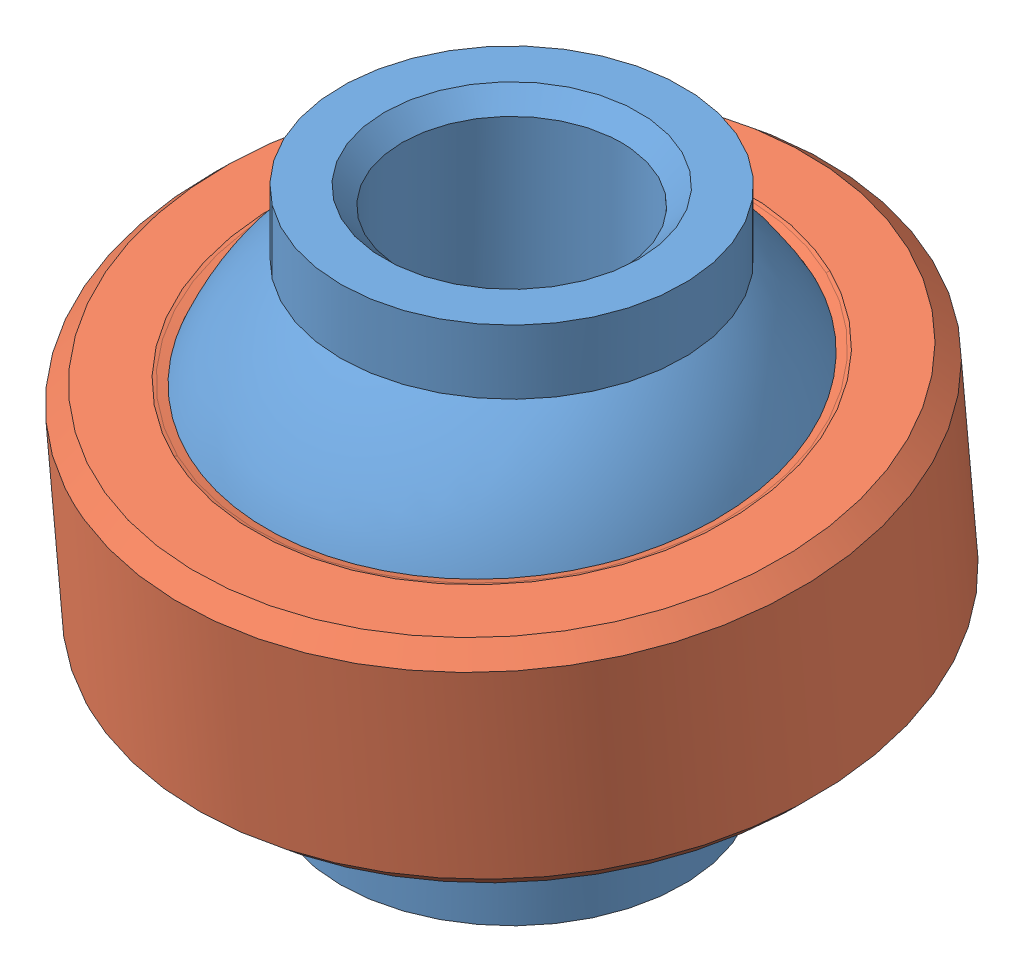
SolidWorks assembly HAB-4T Bearing, configuration Default. Lengths in mm.
Overall size (24.97 15.06 25.44).
2 component instances, 2 part files, 1 mates.
Components (placement in the parent):
- HAB-4T Ball-1: HAB-4T Ball [Default] at origin size (15.06 15.06 15.06)
- HAB-4T Cup-1: HAB-4T Cup [Default] x (0.907526 -0.040168 0.41807) z (-0.41999 -0.081792 0.903836) size (18.8 6.48 18.8)
Mates (geometry in assembly coordinates):
- Coincident3: coincident: point of HAB-4T Ball-1; point of HAB-4T Cup-1
